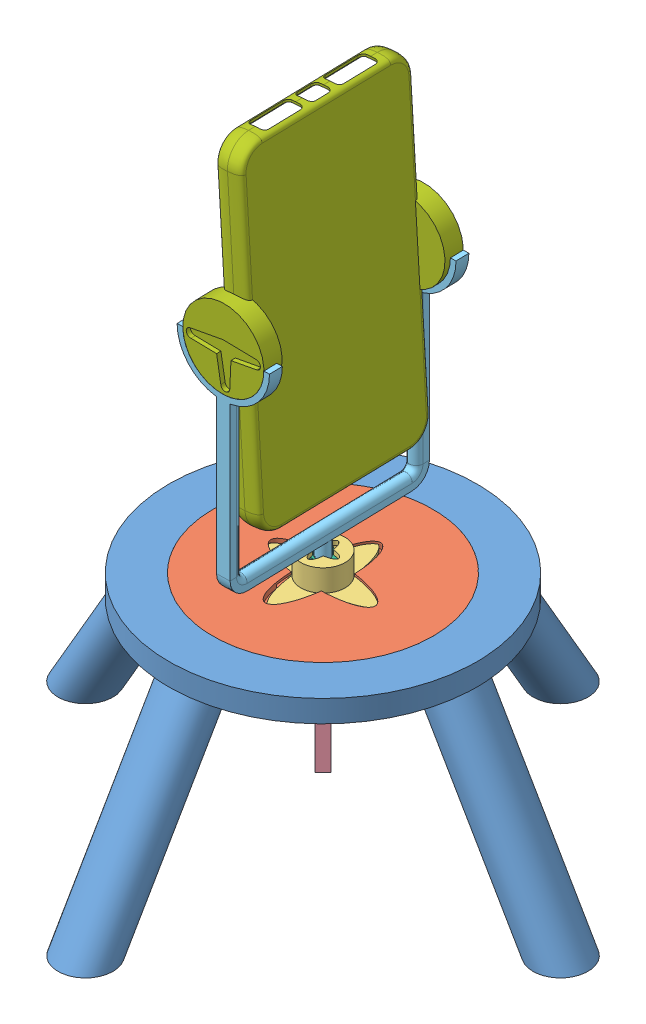
SolidWorks assembly Assem, configuration Default. Lengths in mm.
Overall size (240.97 285.26 240.97).
7 component instances, 7 part files, 14 mates.
Components (placement in the parent):
- OuterBase-1: OuterBase [Default] at (127.0961 70.7107 47.3121) x (1 0 0) z (0 1 0) size (240.97 240.97 96.73)
- Base-2: Base [Default] at (127.0961 80.7107 47.3121) x (0.052628 0 -0.998614) z (-0.998614 0 -0.052628) size (100 5 100)
- Pole-1: Pole [Default] at (127.0961 78.2107 47.3121) x (-0.030278 0 -0.999542) z (0.999542 0 -0.030278) size (50 11.5 50)
- ServoSupport-1: ServoSupport [Default] at (128.8638 43.7107 45.5443) x (0.707107 0 0.707107) z (0 -1 0) size (125 22 30)
- Stand-1: Stand [Default] at (127.0961 83.7107 47.3121) x (-0.024986 0 -0.999688) z (0.999688 0 -0.024986) size (93 124 41)
- StandClamp-1: StandClamp [Default] at (127.0961 85.7107 47.3121) x (-0.484735 0 -0.874661) z (0.874661 0 -0.484735) size (14 2 14)
- Holder-1: Holder [Default] at (127.0958 192.7107 47.3026) x (0.997917 0.059503 -0.024942) z (0.024986 0 0.999688) size (36 151.19 92.98)
Mates (geometry in assembly coordinates):
- Coincident1: coincident: plane of OuterBase-1 through (127.0961 75.7107 47.3121) normal (0 1 0); plane of Base-2 through (127.0961 75.7107 47.3121) normal (0 -1 0)
- Concentric1: concentric: circle of OuterBase-1; circle of Base-2
- Coincident19: coincident: plane of Base-2 through (127.0961 80.7107 47.3121) normal (0 1 0); plane of Pole-1 through (127.0961 80.7107 47.3121) normal (0 -1 0)
- Concentric2: concentric: cylinder of Base-2 through (127.0961 87.7817 47.3121) axis (0 -1 0) radius 2.5; cylinder of Pole-1 through (127.0961 80.7107 47.3121) axis (0 -1 0) radius 2.5
- Parallel11: parallel: face of Base-2; face of Pole-1
- Concentric4: concentric: cylinder of Pole-1 through (127.0961 89.7107 47.3121) axis (0 -1 0) radius 10; cylinder of Stand-1 through (127.0961 94.7107 47.3121) axis (0 -1 0) radius 3
- Coincident28: coincident: plane of Pole-1 through (127.0961 83.7107 47.3121) normal (0 1 0); plane of Stand-1 through (127.0961 83.7107 47.3121) normal (0 -1 0)
- Concentric5: concentric: cylinder of Stand-1 through (127.0961 94.7107 47.3121) axis (0 -1 0) radius 3; cylinder of StandClamp-1 through (127.0961 87.7107 47.3121) axis (0 -1 0) radius 3
- Coincident29: coincident: plane of Pole-1 through (127.0961 85.7107 47.3121) normal (0 1 0); plane of StandClamp-1 through (127.0961 85.7107 47.3121) normal (0 -1 0)
- Concentric6: concentric: cylinder of Stand-1 through (124.7889 192.7107 -44.9985) axis (0.024986 0 0.999688) radius 18; cylinder of Holder-1 through (125.9342 192.7107 0.8266) axis (0.024986 0 0.999688) radius 18
- Coincident30: coincident: plane of Stand-1 through (128.9333 102.7107 0.7516) normal (-0.024986 0 -0.999688); plane of Holder-1 through (125.9342 192.7107 0.8266) normal (-0.024986 0 -0.999688)
- Coincident31: coincident: plane of OuterBase-1 through (86.4374 72.7107 6.6534) normal (0.707107 0 0.707107); plane of ServoSupport-1 through (84.6697 42.7107 8.4212) normal (-0.707107 0 -0.707107)
- Coincident32: coincident: plane of OuterBase-1 through (127.0961 72.7107 47.3121) normal (0 -1 0); plane of ServoSupport-1 through (85.3768 72.7107 9.1283) normal (0 1 0)
- Coincident33: coincident: plane of OuterBase-1 through (125.3283 72.7107 49.0798) normal (0.707107 0 -0.707107); plane of ServoSupport-1 through (125.3283 43.7107 49.0798) normal (-0.707107 0 0.707107)
